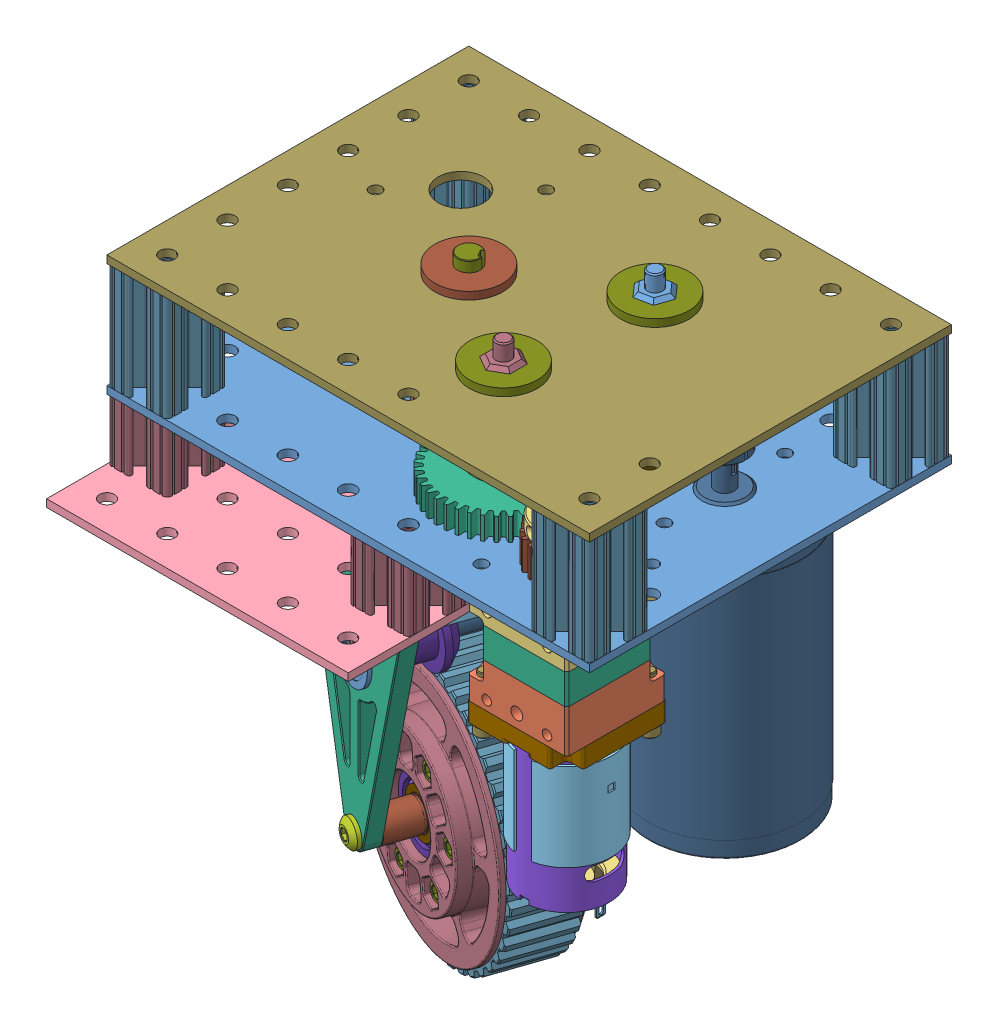
SolidWorks assembly Swerve V2.5 ASM 3_29_14, configuration Default. Lengths in mm.
Overall size (209.41 278.23 177.8).
183 component instances, 89 part files, 115 mates.
Components (placement in the parent):
- Middle Plate V2.5-1: Middle Plate V2.5 [Default] at (-68.3176 37.1134 -104.1218) x (1 0 0) z (0 0 -1) size (203.2 3.17 152.4)
- VEXpro_VersaPlanetary_with_AM9015-1: VEXpro_VersaPlanetary_with_AM9015 [Default] at (93.5566 -4.8866 16.5282) x (0 0 1) z (0 -1 0) size (42.75 42.7 160.22)
  - 217-2625-001 Rev1-1: 217-2625-001 Rev1 [Default] at origin size (42 42 18)
  - 217-2625-002 Rev1-1: 217-2625-002 Rev1 [Default] at (0 0 -16.7) size (42 42 17.13)
  - 217-2625-003 Rev1-1: 217-2625-003 Rev1 [Default] at (0 0 -30.9478) x (1 0 0) z (0 0 -1) size (17 17 64.12)
  - 217-2625-009 Rev1-1: 217-2625-009 Rev1 [Default] at (0 0 -3.48) x (0 -1 0) z (0 0 -1) size (18 18 13)
  - 217-2816-001 Rev1-1: 217-2816-001 Rev1 [Default] at (0 0 -16.85) x (1 0 0) z (0 0 -1) size (42 42 14.5)
  - 217-2625-007 Rev1_Sun_Driver01-1: 217-2625-007 Rev1_Sun_Driver01 [Default] at (0 0 -11.767) x (0.055822 0.998441 0) z (0 0 1) size (14.49 14.49 12.72)
  - 217-2625-100-1: 217-2625-100 [Default] at (0 0 -18.467) x (0 1 0) z (0 0 1) size (39.26 38.9 12.7)
    - 217-2625-008 Rev1-1: 217-2625-008 Rev1 [Default] at origin size (34.7 34.7 4.7)
    - 217-2625-010 Rev1-1: 217-2625-010 Rev1 [Default] at (0 10.193 3.65) x (0.999813 0.019336 0) z (0 0 1) size (4 4 12)
    - 217-2625-010 Rev1-2: 217-2625-010 Rev1 [Default] at (8.691 -5.3258 3.65) size (4 4 12)
    - 217-2625-010 Rev1-3: 217-2625-010 Rev1 [Default] at (-8.691 -5.3258 3.65) size (4 4 12)
    - 217-2625-005 Rev1_Planet_Revolving_Follower01-1: 217-2625-005 Rev1_Planet_Revolving_Follower01 [Default] at (8.691 -5.3258 6.35) x (0.932816 0.360354 0) z (0 0 1) size (16.91 16.92 8)
    - 217-2625-005 Rev1_Planet_Revolving_Follower01-2: 217-2625-005 Rev1_Planet_Revolving_Follower01 [Default] at (-8.691 -5.3258 6.35) x (-0.932788 -0.360426 0) z (0 0 1) size (16.91 16.92 8)
    - 217-2625-005 Rev1_Planet_Revolving_Follower01-3: 217-2625-005 Rev1_Planet_Revolving_Follower01 [Default] at (0 10.193 6.35) x (0.893583 0.448898 0) z (0 0 1) size (16.91 16.92 8)
  - 217-2625-014 Rev1-1: 217-2625-014 Rev1 [Default] at (0 0 1.2558) x (-1 0 0) z (0 -1 0) size (8 7.5 7.93)
  - SSA_SSA0832-0750ZC-1: SSA_SSA0832-0750ZC [Default] at (-17.4921 -17.5079 15.5) x (0.008716 -0.999962 0) z (-0.999962 -0.008716 0) size (6.73 23.11 6.73)
  - 217-2742-1: 217-2742 [Default] at (0 0 -30.4002) x (0 0 1) z (-1 0 0) size (7 28 28)
  - 217-2742-2: 217-2742 [Default] at (0 0 -38.7002) x (0 0 1) z (-0.997393 0.072165 0) size (7 28 28)
  - SSA_SSA0832-1250ZC-1: SSA_SSA0832-1250ZC [Default] at (17.5 -17.5 -34.561) x (1 0 0) z (0 1 0) size (6.73 35.81 6.73)
  - SSA_SSA0832-1250ZC-2: SSA_SSA0832-1250ZC [Default] at (-17.5 17.5 -34.561) x (1 0 0) z (0 1 0) size (6.73 35.81 6.73)
  - SSS1032-0125ZB_94105A824-1: SSS1032-0125ZB_94105A824 [Default] at (-6.908 0 1.995) x (0 -0.92485 0.380331) z (-1 0 0) size (4.83 4.84 3.3)
  - 217-2625-018 Rev1_98541A410-1: 217-2625-018 Rev1_98541A410 [Default] at (0 0 -22.7954) x (0 0 -1) z (0.980859 -0.194721 0) size (1 19.6 17.4)
  - 217-2625-017 Rev1_9714K61-1: 217-2625-017 Rev1_9714K61 [Default] at (0 0 -31.4002) x (-0.695225 0.718792 0) z (-0.718792 -0.695225 0) size (28.51 4.98 30.18)
  - PINL-M020-006-S-1: PINL-M020-006-S [Default] at (-18.5 13.6657 -9.5) x (0 0 -1) z (1 0 0) size (6 2 2)
  - PINL-M020-006-S-2: PINL-M020-006-S [Default] at (-18.5 13.6657 -22.2) x (0 0 -1) z (0.23951 -0.970894 0) size (6 2 2)
  - CCL-9015-am-0912-1: CCL-9015-am-0912 [Default] at (1.5904 1.123 40.182) x (0 0 1) z (1 0 0) size (82.02 37.83 37.47)
    - AM-0912 terminal-1: AM-0912 terminal [Default] at (29.27 -13.055 -1.5854) size (10.06 0.6 3.8)
    - AM-0912 output bushing-1: AM-0912 output bushing [Default] at (-28.166 1.123 -1.5904) size (4.5 10.97 10.97)
    - AM-0912 end cap-1: AM-0912 end cap [Default] at (24.952 1.123 -1.5904) size (6.48 34.65 34.46)
    - AM-0912 cap bushing-1: AM-0912 cap bushing [Default] at (31.302 1.123 -1.5904) size (3.04 8.08 8.08)
    - AM-0912 shield-1: AM-0912 shield [Default] at (-21.634 1.123 -1.5904) x (1 0 0) z (0 -1 0) size (36.88 37.47 37.83)
    - AM-0912 shaft-1: AM-0912 shaft [Default] at (-32.682 1.123 -1.5904) x (1 0 0) z (0 0.970706 0.240271) size (80.92 3.36 3.32)
    - AM-0912 terminal housing-1: AM-0912 terminal housing [Default] at (30.286 -13.101 -1.5904) x (-1 0 0) z (0 0 1) size (4.06 4.83 19.05)
    - AM-0912 terminal housing-2: AM-0912 terminal housing [Default] at (30.286 15.347 -1.5904) x (-1 0 0) z (0 0 -1) size (4.06 4.83 19.05)
    - AM-0912 terminal-2: AM-0912 terminal [Default] at (29.27 15.301 -1.5954) size (10.06 0.6 3.8)
    - AM-0912 housing-1: AM-0912 housing [Default] at (32.318 1.123 -1.5904) size (61.5 35.8 35.8)
  - SSA_SSA0832-0750ZC-2: SSA_SSA0832-0750ZC [Default] at (17.4921 17.5079 15.5) x (-0.008716 0.999962 0) z (0.999962 0.008716 0) size (6.73 23.11 6.73)
  - 217-2822-004 Rev4-1: 217-2822-004 Rev4 [Default] at (0 0 14.5) x (1 0.000449 0) z (0 0 1) size (42 42 9.8)
- 2_5 CIM Motor-1: 2_5 CIM Motor [Default] at (99.1446 26.9384 -44.4318) x (0 0 1) z (0 1 0) size (64.41 64.41 149.33)
- 50 tooth by 0.375 drive gear-2: 50 tooth by 0.375 drive gear [Default] at (-10.8801 58.1827 -17.093) x (1 0 0) z (0 -1 0) size (65.92 65.91 9.53) (hidden)
- 20 Tooth Steering Gear-1: 20 Tooth Steering Gear [Default] at (93.5566 43.4336 16.5282) x (0 0 -1) z (0 1 0) size (28.2 28.2 12.65)
- Top Plate V2.5-1: Top Plate V2.5 [Default] at (-68.343 84.7384 -104.1218) x (1 0 0) z (0 0 -1) size (203.2 3.17 152.4)
- 1020 - 0.875-1: 1020 - 0.875 [Default] at (-587.721 4.5981 961.277) x (0 0 -1) z (0 -1 0) size (25.4 50.8 22.23) (hidden)
- 1020 - 0.875-2: 1020 - 0.875 [Default] at (-587.721 4.5981 808.877) x (0 0 -1) z (0 -1 0) size (25.4 50.8 22.23) (hidden)
- 1020 - 0.875-3: 1020 - 0.875 [Default] at (-967.9477 -17.6269 -627.6227) x (1 0 0) z (0 -1 0) size (25.4 50.8 22.23) (hidden)
- 1020 -1.75-1: 1020 -1.75 [Default] at (-790.1477 78.3884 495.5791) x (1 0 0) z (0 1 0) size (25.4 50.8 44.45) (hidden)
- 1020 -1.75-2: 1020 -1.75 [Default] at (380.7388 -10.5116 942.2077) x (-0.837169 0 -0.546944) z (0 -1 0) size (25.4 50.8 44.45) (hidden)
- 1020 -1.75-3: 1020 -1.75 [Default] at (961.3238 -10.5116 -357.9119) x (-0.546944 0 0.837169) z (0 -1 0) size (25.4 50.8 44.45) (hidden)
- 1020 -1.75-4: 1020 -1.75 [Default] at (-541.0186 78.3884 -876.7519) x (0 0 1) z (0 1 0) size (25.4 50.8 44.45) (hidden)
- 14 Tooth 20 Pitch CIM Pinion-1: 14 Tooth 20 Pitch CIM Pinion [Default] at (99.1446 43.643 -44.4318) x (0.461445 0 -0.887169) z (0.887169 0 0.461445) size (20.28 9.53 20.28) (hidden)
- Hex Idler Shaft Steering-4: Hex Idler Shaft Steering [Default] at (56.752 60.1004 6.3682) x (0 0 1) z (0 -1 0) size (14.73 12.76 65.41)
- RushGears_2010_A2017-1: RushGears_2010_A2017 [2014.5A170.850.3750.380.380.95] at (99.1446 67.4029 -44.4318) x (1 0 0) z (0 -1 0) size (24.1 24.03 9.65)
- Revolution 2 Plaction+Steering Gear-1: Revolution 2 Plaction+Steering Gear [Default] at (-19.6614 -193.5925 -255.7146) x (0.992877 0 0.119145) z (-0.119145 0 0.992877) size (163.7 274.4 125.67)
  - Revolution 2 Plaction-1: Revolution 2 Plaction [Default] at (62.6202 125.584 106.4116) size (163.7 274.4 125.67)
    - cs_drive_hub_asm_1-1: cs_drive_hub_asm_1 [Default] at (28.1074 158.1318 104.3172) x (-0.796969 0 0.60402) z (-0.60402 0 -0.796969) size (89.7 127.05 89.7)
      - 5906K526_thrust_bushing_1-1: 5906K526_thrust_bushing_1 [Default] at (33.9501 -89.5224 3.5116) x (-0.279506 0 -0.960144) z (0 -1 0) size (63.5 63.5 3.17)
      - cs_vert_drive_shaft_1-1: cs_vert_drive_shaft_1 [Default] at (390.5574 -784.499 -2.4616) x (0 1 0) z (0.016748 0 0.99986) size (127.05 9.26 9.53)
      - 6843K12_miter_gear_1-1: 6843K12_miter_gear_1 [Default] at (36.0118 -122.8345 2.5948) x (-0.91373 0 0.406323) z (-0.406323 0 -0.91373) size (27.69 19.05 27.69)
      - revo2_pivot_hub-1: revo2_pivot_hub [Default] at (32.6196 -72.4841 4.7196) x (-0.740355 0 0.672216) z (-0.672216 0 -0.740355) size (63.5 46.42 63.5)
      - brf-06_1-1: brf-06_1 [Default] at (33.9501 -95.4787 3.5116) x (-0.582551 0 0.812794) z (0 -1 0) size (24.59 24.59 7.11)
      - brf-06_1-2: brf-06_1 [Default] at (33.9501 -53.0226 3.5116) x (-0.999614 0 -0.027772) z (0 1 0) size (24.59 24.59 7.11)
      - Imported_1-1: Imported_1 [Default] at (33.9501 -123.279 3.5116) x (0 -1 0) z (0.051397 0 0.998678) size (0.64 12.09 10.6)
      - Imported_1-2: Imported_1 [Default] at (33.9501 -49.0094 3.5116) x (0 1 0) z (0.82628 0 -0.563259) size (0.64 12.09 10.6)
      - large_thrust_bushing_1-1: large_thrust_bushing_1 [Default] at (33.9501 -102.2097 3.5116) x (1 0 0) z (0 -1 0) size (19.05 19.05 1.57)
      - bushing_backer_1-1: bushing_backer_1 [Default] at (33.9501 -99.0347 3.5116) x (1 0 0) z (0 -1 0) size (25.4 25.4 3.17)
    - cs_wheel_box_asm_plaction-1: cs_wheel_box_asm_plaction [Default] at (-5.7354 51.1469 144.7113) x (0.977946 0 0.20886) z (0 1 0) size (149.25 84.94 179.3)
      - revo2_wheel_box_cap-1: revo2_wheel_box_cap [Default] at origin size (63.5 63.5 9.53)
      - 6843K12_miter_gear_1-1: 6843K12_miter_gear_1 [Default] at (1.3308 15.2099 -25.4535) x (-0.668029 0 0.744136) z (0.744136 0 0.668029) size (27.69 19.05 27.69)
      - revo2_side_plate-1: revo2_side_plate [Default] at (-18.57 61.2601 -1.4632) x (1 0 0) z (0 -1 0) size (63.5 106.45 6.35)
      - revo2_side_plate-2: revo2_side_plate [Default] at (18.217 -14.9399 -1.4632) x (-1 0 0) z (0 1 0) size (63.5 106.45 6.35)
      - BHCS_91255A535-1: BHCS_91255A535 [Default] at (-0.1765 -14.9399 -90.5764) x (1 0 0) z (0 -1 0) size (11.23 11.23 13.63)
      - 91251A192_shcs-1: 91251A192_shcs [Default] at (-25.5765 51.7351 4.7625) x (1 0 0) z (0 -1 0) size (6.86 6.86 13.9)
      - 91251A192_shcs-2: 91251A192_shcs [Default] at (25.2235 51.7351 4.7625) x (1 0 0) z (0 -1 0) size (6.86 6.86 13.9)
      - 91251A192_shcs-3: 91251A192_shcs [Default] at (-8.6423 51.7351 4.7665) x (1 0 0) z (0 -1 0) size (6.86 6.86 13.9)
      - 91251A192_shcs-4: 91251A192_shcs [Default] at (8.2893 -5.4149 4.7665) x (1 0 0) z (0 1 0) size (6.86 6.86 13.9)
      - 91251A192_shcs-5: 91251A192_shcs [Default] at (-25.5765 -5.4149 4.7625) x (1 0 0) z (0 1 0) size (6.86 6.86 13.9)
      - 91251A192_shcs-6: 91251A192_shcs [Default] at (25.2235 -5.4149 4.7625) x (1 0 0) z (0 1 0) size (6.86 6.86 13.9)
      - brf-06_1-1: brf-06_1 [Default] at (-0.1765 59.2789 -23.7744) x (1 0 0) z (0 1 0) size (24.59 24.59 7.11)
      - brf-06_1-2: brf-06_1 [Default] at (-0.1765 -12.9587 -23.7744) x (0.755419 0 -0.655243) z (0 -1 0) size (24.59 24.59 7.11)
      - 16t_ws_globe_gear-1: 16t_ws_globe_gear [Default] at (2.3218 39.2687 -25.5275) x (0.818565 0 -0.574414) z (0.574414 0 0.818565) size (35.31 10.29 35.31)
      - revo2_cross_drive_shaft-1: revo2_cross_drive_shaft [Default] at (136.4364 723.0009 -354.9485) x (0 -1 0) z (-0.924435 0 -0.381339) size (83.39 9.26 9.53)
      - Imported_1-1: Imported_1 [Default] at (-0.1765 -16.9719 -23.7744) x (0 1 0) z (0 0 1) size (0.64 12.09 10.6)
      - Imported_1-2: Imported_1 [Default] at (-0.1765 63.4318 -23.7744) x (0 -1 0) z (0 0 1) size (0.64 12.09 10.6)
      - large_thrust_bushing_1-1: large_thrust_bushing_1 [Default] at (-0.1765 -5.4149 -23.7744) x (1 0 0) z (0 1 0) size (19.05 19.05 1.57)
      - 91251A192_shcs-7: 91251A192_shcs [Default] at (8.2893 51.7351 4.7645) x (1 0 0) z (0 -1 0) size (6.86 6.86 13.9)
      - 91251A192_shcs-8: 91251A192_shcs [Default] at (-8.6423 -5.4149 4.7645) x (1 0 0) z (0 1 0) size (6.86 6.86 13.9)
      - Imported_1-3: Imported_1 [Default] at (-0.1765 15.6544 -23.7744) x (0 -1 0) z (0 0 1) size (0.64 12.09 10.6)
      - Imported_1-4: Imported_1 [Default] at (-0.1765 48.5474 -23.7744) x (0 -1 0) z (0 0 1) size (0.64 12.09 10.6)
      - Imported_1-5: Imported_1 [Default] at (-0.1765 37.3714 -23.7744) x (0 1 0) z (0 0 1) size (0.64 12.09 10.6)
      - BHCS_91255A535-2: BHCS_91255A535 [Default] at (-0.1765 61.2601 -90.5764) x (0.396029 0 -0.918238) z (0 1 0) size (11.23 11.23 13.63)
      - revo2_wheel_shaft-1: revo2_wheel_shaft [Default] at (-0.1765 -8.5899 -90.5764) x (0.571408 0 0.820666) z (0 1 0) size (12.7 12.7 63.5)
      - AM_36t_sprocket-1: AM_36t_sprocket [Default] at (-0.1765 48.1029 -90.5764) x (0.524782 0 0.851237) z (0 -1 0) size (82.55 82.55 3.1)
      - 4Plaction-500bearing-1: 4Plaction-500bearing [Default] at (-0.1765 3.3481 -90.5764) x (0 1 0) z (-0.599972 0 0.800021) size (41.66 115.7 115.7)
        - 4MW_d011-1: 4MW_d011 [Default] at origin size (22.87 98.05 98.05)
        - 4MW_d011-2: 4MW_d011 [Default] at (41.656 0 0) x (-1 0 0) z (0 0 -1) size (22.87 98.05 98.05)
        - 4RoughTread1-1: 4RoughTread1 [Default] at (8.128 0 0) x (0 -0.992815 0.119662) z (1 0 0) size (104 104 25.4)
        - 10-32_nylock_nut1-1: 10-32_nylock_nut1 [Default] at (130.8703 19.4882 -76.5177) x (0 -0.340837 0.940122) z (-1 0 0) size (11.68 10.93 7.15)
        - 10-32_nylock_nut1-2: 10-32_nylock_nut1 [Default] at (130.8703 76.0104 -21.3816) x (0 -0.984588 0.174888) z (-1 0 0) size (11.68 10.93 7.15)
        - 10-32_nylock_nut1-3: 10-32_nylock_nut1 [Default] at (130.8703 56.5222 55.1361) x (0 -0.643751 -0.765235) z (-1 0 0) size (11.68 10.93 7.15)
        - 10-32_nylock_nut1-4: 10-32_nylock_nut1 [Default] at (130.8703 -19.4882 76.5177) x (0 0.340837 -0.940122) z (-1 0 0) size (11.68 10.93 7.15)
        - 10-32_nylock_nut1-5: 10-32_nylock_nut1 [Default] at (130.8703 -76.0104 21.3816) x (0 0.984588 -0.174888) z (-1 0 0) size (11.68 10.93 7.15)
        - 10-32_nylock_nut1-6: 10-32_nylock_nut1 [Default] at (130.8703 -56.5222 -55.1361) x (0 0.643751 0.765235) z (-1 0 0) size (11.68 10.93 7.15)
        - 10-32x1375_shcs1-1: 10-32x1375_shcs1 [Default] at (1.5748 0 23.8125) x (0 -0.961068 -0.276312) z (0 0.276312 -0.961068) size (7.82 39.7 7.82)
        - 10-32x1375_shcs1-2: 10-32x1375_shcs1 [Default] at (1.5748 -20.6222 11.9062) x (0 -0.241241 -0.970465) z (0 0.970465 -0.241241) size (7.82 39.7 7.82)
        - 10-32x1375_shcs1-3: 10-32x1375_shcs1 [Default] at (1.5748 -20.6222 -11.9062) x (0 0.719827 -0.694154) z (0 0.694154 0.719827) size (7.82 39.7 7.82)
        - 10-32x1375_shcs1-4: 10-32x1375_shcs1 [Default] at (1.5748 0 -23.8125) x (0 0.961068 0.276312) z (0 -0.276312 0.961068) size (7.82 39.7 7.82)
        - 10-32x1375_shcs1-5: 10-32x1375_shcs1 [Default] at (1.5748 20.6222 -11.9062) x (0 0.241241 0.970465) z (0 -0.970465 0.241241) size (7.82 39.7 7.82)
        - 10-32x1375_shcs1-6: 10-32x1375_shcs1 [Default] at (1.5748 20.6222 11.9062) x (0 -0.719827 0.694154) z (0 -0.694154 -0.719827) size (7.82 39.7 7.82)
      - ball_bearing_60355K150-1: ball_bearing_60355K150 [Default] at (-0.1765 38.5271 -90.5764) x (1 0 0) z (0 1 0) size (28.57 28.57 6.35)
        - NONE-1: NONE [Default] at origin size (28.57 28.57 6.35)
        - NONEA-1: NONEA [Default] at origin size (18.68 18.68 6.35)
        - NONEB-1: NONEB [Default] at origin size (3.43 3.43 3.43)
        - NONEC-1: NONEC [Default] at origin size (3.43 3.43 3.43)
        - NONED-1: NONED [Default] at origin size (3.43 3.43 3.43)
        - NONEE-1: NONEE [Default] at origin size (3.43 3.43 3.43)
        - NONEF-1: NONEF [Default] at origin size (3.43 3.43 3.43)
        - NONEG-1: NONEG [Default] at origin size (3.43 3.43 3.43)
        - NONEH-1: NONEH [Default] at origin size (3.43 3.43 3.43)
        - NONEI-1: NONEI [Default] at origin size (3.43 3.43 3.43)
        - NONEJ-1: NONEJ [Default] at origin size (3.43 3.43 3.43)
        - NONEK-1: NONEK [Default] at origin size (3.43 3.43 3.43)
      - ball_bearing_60355K150-2: ball_bearing_60355K150 [Default] at (-0.1765 9.8251 -90.5764) x (1 0 0) z (0 1 0) size (28.57 28.57 6.35)
        - NONE-1: NONE [Default] at origin size (28.57 28.57 6.35)
        - NONEA-1: NONEA [Default] at origin size (18.68 18.68 6.35)
        - NONEB-1: NONEB [Default] at origin size (3.43 3.43 3.43)
        - NONEC-1: NONEC [Default] at origin size (3.43 3.43 3.43)
        - NONED-1: NONED [Default] at origin size (3.43 3.43 3.43)
        - NONEE-1: NONEE [Default] at origin size (3.43 3.43 3.43)
        - NONEF-1: NONEF [Default] at origin size (3.43 3.43 3.43)
        - NONEG-1: NONEG [Default] at origin size (3.43 3.43 3.43)
        - NONEH-1: NONEH [Default] at origin size (3.43 3.43 3.43)
        - NONEI-1: NONEI [Default] at origin size (3.43 3.43 3.43)
        - NONEJ-1: NONEJ [Default] at origin size (3.43 3.43 3.43)
        - NONEK-1: NONEK [Default] at origin size (3.43 3.43 3.43)
      - bushing_backer_1-1: bushing_backer_1 [Default] at (-0.1765 -5.4149 -23.7744) x (1 0 0) z (0 -1 0) size (25.4 25.4 3.17)
      - 90128A218-1: 90128A218 [Default] at (-22.1736 35.8601 14.097) size (7.92 7.92 14.58)
      - 90128A218-2: 90128A218 [Default] at (-22.1736 10.4601 14.097) x (0.5 0.866025 0) z (0 0 1) size (7.92 7.92 14.58)
      - 90128A218-3: 90128A218 [Default] at (-0.1765 -2.2399 14.097) x (-0.5 0.866025 0) z (0 0 1) size (7.92 7.92 14.58)
      - 90128A218-4: 90128A218 [Default] at (21.8205 10.4601 14.097) x (-1 0 0) z (0 0 1) size (7.92 7.92 14.58)
      - 90128A218-5: 90128A218 [Default] at (21.8205 35.8601 14.097) x (-0.5 -0.866025 0) z (0 0 1) size (7.92 7.92 14.58)
      - 90128A218-6: 90128A218 [Default] at (-0.1765 48.5601 14.097) x (0.5 -0.866025 0) z (0 0 1) size (7.92 7.92 14.58)
    - bushing_hub_asm_1-1: bushing_hub_asm_1 [Default] at (11.3553 106.7094 120.0903) x (0.988095 0 -0.153847) z (-0.153847 0 -0.988095) size (63.5 38.1 63.5)
      - revo2_steering_hub_1-1: revo2_steering_hub_1 [Default] at origin size (63.5 38.1 63.5)
      - 1_1-1: 1_1 [Default] at (-0.595 0 0) size (44.45 38.1 44.45)
  - 40 Tooth Steering Gear+Mounting Holes-2: 40 Tooth Steering Gear+Mounting Holes [default] at (61.5494 237.4369 228.4366) x (0.982925 0 0.184009) z (0 1 0) size (53.25 53.25 11.09)
  - fhcs_91253A238-2: fhcs_91253A238 [Default] at (71.8811 238.9736 216.3838) x (1 0 0) z (0 1 0) size (10.32 10.32 6.54)
  - fhcs_91253A238-3: fhcs_91253A238 [Default] at (66.8216 238.9736 243.4106) x (1 0 0) z (0 1 0) size (10.32 10.32 6.54)
  - fhcs_91253A238-4: fhcs_91253A238 [Default] at (45.9455 238.9736 225.5155) x (1 0 0) z (0 1 0) size (10.32 10.32 6.54)
- .5 in Hex Flange Bearing-1: .5 in Hex Flange Bearing [Default] at (56.752 87.9134 6.3682) x (-0.866025 0 -0.5) z (-0.5 0 0.866025) size (31.12 7.94 31.12)
- .5 in Hex Flange Bearing-2: .5 in Hex Flange Bearing [Default] at (56.752 30.7634 6.3682) x (0.866025 0 -0.5) z (0.5 0 0.866025) size (31.12 7.94 31.12)
- .5 in Hex Flange Bearing-3: .5 in Hex Flange Bearing [Default] at (63.4068 87.9134 -50.7818) x (-0.321696 0 0.946843) z (0.946843 0 0.321696) size (31.12 7.94 31.12)
- .5 in Hex Flange Bearing-4: .5 in Hex Flange Bearing [Default] at (63.4322 33.9384 -50.7818) x (-0.321696 0 0.946843) z (-0.946843 0 -0.321696) size (31.12 7.94 31.12)
- 40 Tooth Drive Idler Gear-6: 40 Tooth Drive Idler Gear [Default] at (63.4322 62.5134 -50.7818) x (-0.194824 0 -0.980838) z (0 1 0) size (53.62 53.62 9.53)
- Bearing Spacer-2: Bearing Spacer [Default] at (63.4322 37.1134 -50.7818) size (44.45 3.17 44.45)
- Hex Idler Shaft Drive-5: Hex Idler Shaft Drive [Default] at (63.4322 61.6879 -50.7818) x (-0.321696 0 0.946843) z (0 -1 0) size (14.73 12.76 62.23)
- 50 tooth by 0.375 drive gear-3: 50 tooth by 0.375 drive gear [Default] at (14.2324 59.3384 -21.5718) x (0.996485 0 -0.083776) z (0 -1 0) size (65.92 65.91 9.53)
- .5 in Hex Collar-1: .5 in Hex Collar [Default] at (63.4322 54.5759 -50.7818) x (0.980838 0 -0.194824) z (0 -1 0) size (25.39 25.4 7.82)
- .5 in Hex Collar-2: .5 in Hex Collar [Default] at (63.4322 70.4509 -50.7818) x (0.980838 0 -0.194824) z (0 -1 0) size (25.39 25.4 7.82)
- .5 in Hex Collar-3: .5 in Hex Collar [Default] at (93.5566 52.9332 16.5282) x (0.5 0 0.866025) z (0 1 0) size (25.39 25.4 7.82)
- .5 in Hex Collar-5: .5 in Hex Collar [Default] at (56.752 54.5251 6.3682) x (0.982551 0 -0.185995) z (0 -1 0) size (25.39 25.4 7.82)
- Bottom Plate V2.5-2: Bottom Plate V2.5 [Default] at (-68.3176 8.5384 -104.1218) x (1 0 0) z (0 0 -1) size (127 3.17 177.8)
- .375 in Round Collar-1: .375 in Round Collar [Default] at (14.2324 54.5759 -21.5718) x (1 0 0) z (0 -1 0) size (22.21 22.23 6.35)
- .375 in Round Collar-2: .375 in Round Collar [Default] at (14.2324 70.4509 -21.5718) x (1 0 0) z (0 -1 0) size (22.21 22.23 6.35)
- 40 Tooth Gear-7: 40 Tooth Gear [Default] at (56.752 45.0255 6.3682) x (1 0 0) z (0 1 0) size (53.62 53.62 12.65)
- .0265 Hex D Spacer .5 Wide-1: .0265 Hex D Spacer .5 Wide [Default] at (93.5566 36.6074 16.5282) x (1 0 0) z (0 1 0) size (19.5 19.5 1.59)
- .5 in Hex Collar-7: .5 in Hex Collar [Default] at (63.4322 46.6384 -50.7818) x (1 0 0) z (0 1 0) size (25.39 25.4 7.82)
- .5 in Hex Collar-8: .5 in Hex Collar [Default] at (56.752 70.4509 6.3682) x (1 0 0) z (0 1 0) size (25.39 25.4 7.82)
- .0625 in Hex Delrin Spacer .5 Wide-2: .0625 in Hex Delrin Spacer .5 Wide [Default] at (63.4322 42.6697 -50.7818) x (0.321696 0 -0.946843) z (0 1 0) size (19.5 19.5 1.59)
- .25 in Hex Delrin Spacer .5 Wide-1: .25 in Hex Delrin Spacer .5 Wide [Default] at (63.4322 76.8009 -50.7818) x (0.321696 0 -0.946843) z (0 1 0) size (19.5 19.5 6.35)
- .25 in Hex Delrin Spacer .5 Wide-2: .25 in Hex Delrin Spacer .5 Wide [Default] at (56.752 76.8009 6.3682) x (0 0 -1) z (0 -1 0) size (19.5 19.5 6.35)
- CIM Collar-1: CIM Collar [Default] at (99.1446 54.5759 -44.4318) x (1 0 0) z (0 -1 0) size (17.99 18 6.35)
- .375x1.125 in Flanged Bearing-1: .375x1.125 in Flanged Bearing [Default] at (14.2324 87.9134 -21.5718) x (-0.837169 0 -0.546944) z (-0.546944 0 0.837169) size (31.12 7.94 31.12)
- .25 in Hex Delrin Spacer .375 Wide-1: .25 in Hex Delrin Spacer .375 Wide [Default] at (14.2324 76.8009 -21.5718) x (1 0 0) z (0 1 0) size (15.88 15.88 6.35)
- 1.0 in 8020 Stand-1: 1.0 in 8020 Stand [Default] at (-855.9566 8.5384 -680.2626) x (1 0 0) z (0 -1 0) size (25.4 25.4 25.4)
- 1.0 in 8020 Stand-2: 1.0 in 8020 Stand [Default] at (-855.9566 8.5384 -553.2626) x (1 0 0) z (0 -1 0) size (25.4 25.4 25.4)
- 1.0 in 8020 Stand-3: 1.0 in 8020 Stand [Default] at (-754.3566 8.5384 -553.2626) x (1 0 0) z (0 -1 0) size (25.4 25.4 25.4)
- 1.0 in 8020 Stand-4: 1.0 in 8020 Stand [Default] at (-754.3566 33.9384 497.419) x (1 0 0) z (0 1 0) size (25.4 25.4 25.4)
- 1.75 in 8020 Stand-1: 1.75 in 8020 Stand [Default] at (-855.9566 37.1134 -553.2626) x (1 0 0) z (0 -1 0) size (25.4 25.4 44.45)
- 1.75 in 8020 Stand-2: 1.75 in 8020 Stand [Default] at (-678.1566 37.1134 -553.2626) x (1 0 0) z (0 -1 0) size (25.4 25.4 44.45)
- 1.75 in 8020 Stand-3: 1.75 in 8020 Stand [Default] at (-678.1566 37.1134 -680.2626) x (1 0 0) z (0 -1 0) size (25.4 25.4 44.45)
- 1.75 in 8020 Stand-4: 1.75 in 8020 Stand [Default] at (-855.9566 37.1134 -680.2626) x (1 0 0) z (0 -1 0) size (25.4 25.4 44.45)
Mates (geometry in assembly coordinates):
- Coincident11: coincident anti-aligned: plane of Middle Plate V2.5-1 through (-68.3176 33.9384 -104.1218) normal (0 -1 0); plane of 2_5 CIM Motor-1 through (99.1446 33.9384 -44.4318) normal (0 1 0)
- Distance4: distance = 3.429 mm aligned: plane of 50 tooth by 0.375 drive gear-2 through (-4.1614 66.1202 13.0744) normal (0 1 0); plane of 2_5 CIM Motor-1 through (99.1446 69.5492 -44.4318) normal (0 1 0)
- Distance5: distance = 44.45 mm anti-aligned: plane of Top Plate V2.5-1 through (-68.343 81.5634 -104.1218) normal (0 -1 0); plane of Middle Plate V2.5-1 through (-68.3176 37.1134 -104.1218) normal (0 1 0)
- Concentric15: concentric aligned: cylinder of Top Plate V2.5-1 through (56.752 106.9634 6.3682) axis (0 -1 0) radius 14.2875; cylinder of Middle Plate V2.5-1 through (56.752 84.7384 6.3682) axis (0 -1 0) radius 14.2875
- Concentric18: concentric aligned: cylinder of Middle Plate V2.5-1 through (-55.6176 39.0184 -15.2218) axis (0 -1 0) radius 3.2512; cylinder of 1020 - 0.875-3 through (-55.6176 4.5981 -15.2218) axis (0 -1 0) radius 2.6035
- Concentric19: concentric aligned: cylinder of Middle Plate V2.5-1 through (-55.6176 39.0184 -40.6218) axis (0 -1 0) radius 3.2512; cylinder of 1020 - 0.875-3 through (-55.6176 4.5981 -40.6218) axis (0 -1 0) radius 2.6035
- Concentric22: concentric anti-aligned: cylinder of Middle Plate V2.5-1 through (122.1824 39.0184 -91.4218) axis (0 -1 0) radius 3.2512; cylinder of 1020 -1.75-1 through (122.1824 33.9384 -91.4218) axis (0 1 0) radius 2.6035
- Coincident19: coincident aligned: plane of Middle Plate V2.5-1 through (-68.3176 33.9384 -104.1218) normal (0 -1 0); plane of 1020 -1.75-1 through (134.8824 33.9384 -106.7634) normal (0 -1 0)
- Concentric25: concentric anti-aligned: cylinder of Middle Plate V2.5-1 through (45.9824 39.0184 35.5782) axis (0 -1 0) radius 3.2512; cylinder of 1020 -1.75-4 through (45.9824 33.9384 35.5782) axis (0 1 0) radius 2.6035
- Coincident20: coincident aligned: plane of Middle Plate V2.5-1 through (-68.3176 33.9384 -104.1218) normal (0 -1 0); plane of 1020 -1.75-4 through (61.324 33.9384 48.2782) normal (0 -1 0)
- Coincident21: coincident anti-aligned: plane of Middle Plate V2.5-1 through (-68.3176 33.9384 -104.1218) normal (0 -1 0); plane of 1020 -1.75-2 through (-64.2201 33.9384 -67.9946) normal (0 1 0)
- Coincident22: coincident anti-aligned: plane of Middle Plate V2.5-1 through (-68.3176 33.9384 -104.1218) normal (0 -1 0); plane of 1020 -1.75-3 through (-48.8785 33.9384 87.047) normal (0 1 0)
- Concentric49: concentric anti-aligned: cylinder of 2_5 CIM Motor-1 through (99.1446 37.9262 -44.4318) axis (0 1 0) radius 3.9751; cylinder of 14 Tooth 20 Pitch CIM Pinion-1 through (99.1446 53.168 -44.4318) axis (0 -1 0) radius 4
- Concentric59: concentric anti-aligned: cylinder of 2_5 CIM Motor-1 through (99.1446 37.9262 -44.4318) axis (0 1 0) radius 3.9751; cylinder of RushGears_2010_A2017-1 through (99.1446 12767.4029 -44.4318) axis (0 -1 0) radius 3.9624
- Parallel2: parallel aligned: plane of Middle Plate V2.5-1 through (-68.3176 33.9384 48.2782) normal (0 0 1); plane of Top Plate V2.5-1 through (-68.343 81.5634 48.2782) normal (0 0 1)
- Concentric61: concentric aligned: cylinder of Top Plate V2.5-1 through (56.752 106.9634 6.3682) axis (0 -1 0) radius 14.2875; cylinder of .5 in Hex Flange Bearing-1 through (56.752 87.9134 6.3682) axis (0 -1 0) radius 14.2748
- Coincident42: coincident anti-aligned: plane of Top Plate V2.5-1 through (-68.343 81.5634 -104.1218) normal (0 -1 0); plane of .5 in Hex Flange Bearing-1 through (43.2788 81.5634 -1.4106) normal (0 1 0)
- Concentric62: concentric anti-aligned: cylinder of Middle Plate V2.5-1 through (56.752 84.7384 6.3682) axis (0 -1 0) radius 14.2875; cylinder of .5 in Hex Flange Bearing-2 through (56.752 30.7634 6.3682) axis (0 1 0) radius 14.2748
- Parallel3: parallel anti-aligned: plane of Hex Idler Shaft Steering-4 through (59.9415 30.7624 11.8927) normal (0.5 0 0.866025); plane of .5 in Hex Flange Bearing-1 through (63.112 87.9134 10.0401) normal (-0.5 0 -0.866025)
- Parallel4: parallel anti-aligned: plane of Hex Idler Shaft Steering-4 through (59.9415 30.7624 11.8927) normal (0.5 0 0.866025); plane of .5 in Hex Flange Bearing-2 through (56.752 30.7634 13.7121) normal (-0.5 0 -0.866025)
- Concentric64: concentric anti-aligned: circle of Middle Plate V2.5-1; circle of .5 in Hex Flange Bearing-4
- Concentric65: concentric aligned: circle of Top Plate V2.5-1; circle of .5 in Hex Flange Bearing-3
- Coincident50: coincident anti-aligned: plane of Top Plate V2.5-1 through (-68.343 81.5634 -104.1218) normal (0 -1 0); plane of .5 in Hex Flange Bearing-3 through (58.402 81.5634 -36.0513) normal (0 1 0)
- Concentric68: concentric aligned: cylinder of Hex Idler Shaft Steering-4 through (56.752 96.1684 6.3682) axis (0 1 0) radius 3.1623; circle of .5 in Hex Flange Bearing-1
- Concentric74: concentric anti-aligned: cylinder of Middle Plate V2.5-1 through (99.1446 84.7384 -44.4318) axis (0 -1 0) radius 9.525; cylinder of 2_5 CIM Motor-1 through (99.1446 33.9384 -44.4318) axis (0 1 0) radius 9.525
- Coincident63: coincident anti-aligned: plane of Middle Plate V2.5-1 through (-68.3176 37.1134 -104.1218) normal (0 1 0); plane of .5 in Hex Flange Bearing-2 through (70.2252 37.1134 -1.4106) normal (0 -1 0)
- Coincident64: coincident anti-aligned: plane of Middle Plate V2.5-1 through (-68.3176 37.1134 -104.1218) normal (0 1 0); plane of Bearing Spacer-2 through (63.4322 37.1134 -50.7818) normal (0 -1 0)
- Concentric78: concentric aligned: circle of Middle Plate V2.5-1; circle of Bearing Spacer-2
- Coincident65: coincident anti-aligned: plane of .5 in Hex Flange Bearing-4 through (58.4274 40.2884 -36.0513) normal (0 -1 0); plane of Bearing Spacer-2 through (63.4322 40.2884 -50.7818) normal (0 1 0)
- Coincident66: coincident aligned: plane of Hex Idler Shaft Steering-4 through (56.752 30.7634 13.7342) normal (0 -1 0); plane of .5 in Hex Flange Bearing-2 through (69.1143 30.7634 -0.7692) normal (0 -1 0)
- Concentric79: concentric anti-aligned: circle of .5 in Hex Flange Bearing-4; cylinder of Hex Idler Shaft Drive-5 through (63.4322 96.1684 -50.7818) axis (0 1 0) radius 3.1623
- Parallel12: parallel anti-aligned: plane of .5 in Hex Flange Bearing-3 through (58.5661 87.9134 -56.3046) normal (0.194824 0 0.980838); plane of Hex Idler Shaft Drive-5 through (62.1894 33.9374 -57.0387) normal (-0.194824 0 -0.980838)
- Parallel13: parallel aligned: plane of .5 in Hex Flange Bearing-4 through (61.0697 33.9384 -43.8283) normal (-0.194824 0 -0.980838); plane of Hex Idler Shaft Drive-5 through (62.1894 33.9374 -57.0387) normal (-0.194824 0 -0.980838)
- Coincident69: coincident aligned: plane of .5 in Hex Flange Bearing-4 through (58.84 33.9384 -37.2658) normal (0 -1 0); plane of Hex Idler Shaft Drive-5 through (61.0626 33.9384 -43.8074) normal (0 -1 0)
- Concentric80: concentric anti-aligned: cylinder of Revolution 2 Plaction+Steering Gear-1/Revolution 2 Plaction-1/cs_drive_hub_asm_1-1/cs_vert_drive_shaft_1-1 through (14.2324 66.933 -21.5718) axis (0 1 0) radius 4.7625; cylinder of 50 tooth by 0.375 drive gear-3 through (14.2324 67.2759 -21.5718) axis (0 -1 0) radius 4.7625
- Concentric81: concentric anti-aligned: cylinder of Hex Idler Shaft Drive-5 through (63.4322 96.1684 -50.7818) axis (0 1 0) radius 3.1623; circle of .5 in Hex Collar-1
- Concentric82: concentric anti-aligned: cylinder of Hex Idler Shaft Drive-5 through (63.4322 96.1684 -50.7818) axis (0 1 0) radius 3.1623; circle of .5 in Hex Collar-2
- Parallel14: parallel aligned: plane of Hex Idler Shaft Drive-5 through (62.1894 33.9374 -57.0387) normal (-0.194824 0 -0.980838); plane of .5 in Hex Collar-2 through (68.3619 73.6259 -45.1575) normal (-0.194824 0 -0.980838)
- Parallel15: parallel aligned: plane of Hex Idler Shaft Drive-5 through (62.1894 33.9374 -57.0387) normal (-0.194824 0 -0.980838); plane of .5 in Hex Collar-1 through (68.3619 57.7509 -45.1575) normal (-0.194824 0 -0.980838)
- Parallel16: parallel anti-aligned: plane of 40 Tooth Drive Idler Gear-6 through (58.5701 68.838 -56.329) normal (0.194824 0 0.980838); plane of Hex Idler Shaft Drive-5 through (62.1894 33.9374 -57.0387) normal (-0.194824 0 -0.980838)
- Concentric83: concentric anti-aligned: circle of 20 Tooth Steering Gear-1; circle of .5 in Hex Collar-3
- Coincident77: coincident anti-aligned: plane of 20 Tooth Steering Gear-1 through (93.5566 49.7582 16.5282) normal (0 1 0); plane of .5 in Hex Collar-3 through (93.5566 49.7582 16.5282) normal (0 -1 0)
- Concentric85: concentric anti-aligned: cylinder of Hex Idler Shaft Steering-4 through (56.752 96.1684 6.3682) axis (0 1 0) radius 3.1623; circle of .5 in Hex Collar-5
- Coincident84: coincident aligned: plane of Middle Plate V2.5-1 through (-68.3176 33.9384 -104.1218) normal (-1 0 0); plane of Bottom Plate V2.5-2 through (-68.3176 5.3634 -104.1218) normal (-1 0 0)
- Distance6: distance = 25.4 mm anti-aligned: plane of Bottom Plate V2.5-2 through (-68.3176 8.5384 -104.1218) normal (0 1 0); plane of Middle Plate V2.5-1 through (-68.3176 33.9384 -104.1218) normal (0 -1 0)
- Concentric88: concentric aligned: cylinder of Middle Plate V2.5-1 through (14.2324 84.7384 -21.5718) axis (0 -1 0) radius 25.4762; cylinder of Revolution 2 Plaction+Steering Gear-1/Revolution 2 Plaction-1/bushing_hub_asm_1-1/revo2_steering_hub_1-1 through (14.2324 38.7009 -21.5718) axis (0 -1 0) radius 25.4
- Coincident88: coincident anti-aligned: plane of Revolution 2 Plaction+Steering Gear-1/Revolution 2 Plaction-1/bushing_hub_asm_1-1/revo2_steering_hub_1-1 through (14.2324 5.3634 -21.5718) normal (0 1 0); plane of Bottom Plate V2.5-2 through (-68.3176 5.3634 -104.1218) normal (0 -1 0)
- Concentric89: concentric aligned: cylinder of Revolution 2 Plaction+Steering Gear-1/Revolution 2 Plaction-1/bushing_hub_asm_1-1/revo2_steering_hub_1-1 through (14.2324 38.7009 -21.5718) axis (0 -1 0) radius 25.4; cylinder of Bottom Plate V2.5-2 through (14.2324 8.5384 -21.5718) axis (0 -1 0) radius 25.4
- Concentric90: concentric anti-aligned: cylinder of Revolution 2 Plaction+Steering Gear-1/Revolution 2 Plaction-1/cs_drive_hub_asm_1-1/cs_vert_drive_shaft_1-1 through (14.2324 66.933 -21.5718) axis (0 1 0) radius 4.7625; circle of .375 in Round Collar-2
- Concentric91: concentric anti-aligned: cylinder of Revolution 2 Plaction+Steering Gear-1/Revolution 2 Plaction-1/cs_drive_hub_asm_1-1/cs_vert_drive_shaft_1-1 through (14.2324 66.933 -21.5718) axis (0 1 0) radius 4.7625; circle of .375 in Round Collar-1
- Coincident89: coincident anti-aligned: plane of 50 tooth by 0.375 drive gear-3 through (23.4548 67.2759 7.9267) normal (0 1 0); plane of .375 in Round Collar-2 through (14.2324 67.2759 -21.5718) normal (0 -1 0)
- Coincident90: coincident anti-aligned: plane of 50 tooth by 0.375 drive gear-3 through (23.4548 57.7509 7.9267) normal (0 -1 0); plane of .375 in Round Collar-1 through (14.2324 57.7509 -21.5718) normal (0 1 0)
- Concentric92: concentric aligned: circle of Middle Plate V2.5-1; circle of 40 Tooth Gear-7
- Parallel19: parallel aligned: plane of Hex Idler Shaft Steering-4 through (59.9415 30.7624 11.8927) normal (0.5 0 0.866025); plane of 40 Tooth Gear-7 through (50.3639 51.3501 2.68) normal (0.5 0 0.866025)
- Coincident92: coincident anti-aligned: plane of .5 in Hex Collar-5 through (56.752 51.3501 6.3682) normal (0 -1 0); plane of 40 Tooth Gear-7 through (56.752 51.3501 6.3682) normal (0 1 0)
- Coincident95: coincident anti-aligned: plane of .5 in Hex Flange Bearing-2 through (62.2512 38.7009 3.1932) normal (0 1 0); plane of 40 Tooth Gear-7 through (56.752 38.7009 6.3682) normal (0 -1 0)
- Coincident102: coincident aligned: plane of RushGears_2010_A2017-1 through (99.1446 57.7509 -44.4318) normal (0 -1 0); plane of 40 Tooth Drive Idler Gear-6 through (37.2732 57.7509 -45.5859) normal (0 -1 0)
- Concentric97: concentric anti-aligned: circle of .5 in Hex Flange Bearing-4; circle of .5 in Hex Collar-7
- Concentric98: concentric anti-aligned: circle of .5 in Hex Flange Bearing-4; circle of .0625 in Hex Delrin Spacer .5 Wide-2
- Parallel21: parallel anti-aligned: plane of Hex Idler Shaft Drive-5 through (62.1894 33.9374 -57.0387) normal (-0.194824 0 -0.980838); plane of .0625 in Hex Delrin Spacer .5 Wide-2 through (65.8381 43.4634 -57.8633) normal (0.194824 0 0.980838)
- Coincident104: coincident anti-aligned: plane of .5 in Hex Flange Bearing-4 through (61.3894 41.8759 -44.7694) normal (0 1 0); plane of .0625 in Hex Delrin Spacer .5 Wide-2 through (63.4322 41.8759 -50.7818) normal (0 -1 0)
- Coincident105: coincident anti-aligned: plane of .5 in Hex Collar-7 through (63.4322 43.4634 -50.7818) normal (0 -1 0); plane of .0625 in Hex Delrin Spacer .5 Wide-2 through (63.4322 43.4634 -50.7818) normal (0 1 0)
- Coincident110: coincident anti-aligned: plane of 40 Tooth Drive Idler Gear-6 through (63.4322 67.2759 -50.7818) normal (0 1 0); plane of .5 in Hex Collar-2 through (63.4322 67.2759 -50.7818) normal (0 -1 0)
- Concentric100: concentric anti-aligned: circle of Middle Plate V2.5-1; circle of 40 Tooth Drive Idler Gear-6
- Coincident111: coincident anti-aligned: plane of 40 Tooth Drive Idler Gear-6 through (37.2732 57.7509 -45.5859) normal (0 -1 0); plane of .5 in Hex Collar-1 through (63.4322 57.7509 -50.7818) normal (0 1 0)
- Concentric101: concentric anti-aligned: circle of .5 in Hex Flange Bearing-4; circle of .25 in Hex Delrin Spacer .5 Wide-1
- Parallel23: parallel anti-aligned: plane of Hex Idler Shaft Drive-5 through (62.1894 33.9374 -57.0387) normal (-0.194824 0 -0.980838); plane of .25 in Hex Delrin Spacer .5 Wide-1 through (65.8381 79.9759 -57.8633) normal (0.194824 0 0.980838)
- Coincident113: coincident anti-aligned: plane of .5 in Hex Flange Bearing-3 through (61.364 79.9759 -44.7694) normal (0 -1 0); plane of .25 in Hex Delrin Spacer .5 Wide-1 through (63.4322 79.9759 -50.7818) normal (0 1 0)
- Coincident114: coincident anti-aligned: plane of .5 in Hex Collar-2 through (63.4322 73.6259 -50.7818) normal (0 1 0); plane of .25 in Hex Delrin Spacer .5 Wide-1 through (63.4322 73.6259 -50.7818) normal (0 -1 0)
- Concentric102: concentric anti-aligned: circle of Middle Plate V2.5-1; circle of .5 in Hex Collar-8
- Concentric103: concentric anti-aligned: circle of Middle Plate V2.5-1; circle of .25 in Hex Delrin Spacer .5 Wide-2
- Parallel24: parallel anti-aligned: plane of Hex Idler Shaft Steering-4 through (53.5624 30.7624 11.8927) normal (-0.5 0 0.866025); plane of .25 in Hex Delrin Spacer .5 Wide-2 through (56.752 73.6259 13.8472) normal (0.5 0 -0.866025)
- Coincident116: coincident anti-aligned: plane of .5 in Hex Collar-8 through (56.752 73.6259 6.3682) normal (0 1 0); plane of .25 in Hex Delrin Spacer .5 Wide-2 through (56.752 73.6259 6.3682) normal (0 -1 0)
- Coincident117: coincident anti-aligned: plane of .5 in Hex Flange Bearing-1 through (51.2527 79.9759 3.1932) normal (0 -1 0); plane of .25 in Hex Delrin Spacer .5 Wide-2 through (56.752 79.9759 6.3682) normal (0 1 0)
- Concentric105: concentric anti-aligned: circle of 2_5 CIM Motor-1; circle of CIM Collar-1
- Coincident118: coincident aligned: plane of RushGears_2010_A2017-1 through (99.1446 57.7509 -44.4318) normal (0 -1 0); circle of CIM Collar-1
- Coincident122: coincident anti-aligned: plane of Top Plate V2.5-1 through (-68.343 81.5634 -104.1218) normal (0 -1 0); plane of .375x1.125 in Flanged Bearing-1 through (1.2081 81.5634 -30.0809) normal (0 1 0)
- Concentric108: concentric aligned: cylinder of Revolution 2 Plaction+Steering Gear-1/Revolution 2 Plaction-1/cs_drive_hub_asm_1-1/cs_vert_drive_shaft_1-1 through (14.2324 66.933 -21.5718) axis (0 1 0) radius 4.7625; circle of .375x1.125 in Flanged Bearing-1
- Concentric109: concentric anti-aligned: cylinder of Revolution 2 Plaction+Steering Gear-1/Revolution 2 Plaction-1/cs_drive_hub_asm_1-1/cs_vert_drive_shaft_1-1 through (14.2324 66.933 -21.5718) axis (0 1 0) radius 4.7625; circle of .25 in Hex Delrin Spacer .375 Wide-1
- Coincident123: coincident anti-aligned: plane of .375x1.125 in Flanged Bearing-1 through (10.2454 79.9759 -24.1766) normal (0 -1 0); plane of .25 in Hex Delrin Spacer .375 Wide-1 through (14.2324 79.9759 -21.5718) normal (0 1 0)
- Coincident124: coincident anti-aligned: plane of .375 in Round Collar-2 through (14.2324 73.6259 -21.5718) normal (0 1 0); plane of .25 in Hex Delrin Spacer .375 Wide-1 through (14.2324 73.6259 -21.5718) normal (0 -1 0)
- Coincident125: coincident anti-aligned: plane of Bottom Plate V2.5-2 through (-68.3176 8.5384 -104.1218) normal (0 1 0); plane of 1.0 in 8020 Stand-2 through (-42.9176 8.5384 25.5198) normal (0 -1 0)
- Concentric110: concentric aligned: cylinder of 1.0 in 8020 Stand-2 through (-55.6176 33.9384 35.5782) axis (0 -1 0) radius 2.6035; cylinder of Bottom Plate V2.5-2 through (-55.6176 8.5384 35.5782) axis (0 -1 0) radius 3.175
- Coincident126: coincident aligned: plane of Bottom Plate V2.5-2 through (-68.3176 5.3634 -104.1218) normal (-1 0 0); plane of 1.0 in 8020 Stand-2 through (-68.3176 33.9384 45.1286) normal (-1 0 0)
- Coincident127: coincident anti-aligned: plane of Bottom Plate V2.5-2 through (-68.3176 8.5384 -104.1218) normal (0 1 0); plane of 1.0 in 8020 Stand-1 through (-42.9176 8.5384 -101.4802) normal (0 -1 0)
- Concentric111: concentric aligned: cylinder of Bottom Plate V2.5-2 through (-55.6176 8.5384 -91.4218) axis (0 -1 0) radius 3.175; cylinder of 1.0 in 8020 Stand-1 through (-55.6176 33.9384 -91.4218) axis (0 -1 0) radius 2.6035
- Coincident128: coincident aligned: plane of Bottom Plate V2.5-2 through (-68.3176 5.3634 -104.1218) normal (-1 0 0); plane of 1.0 in 8020 Stand-1 through (-68.3176 33.9384 -81.8714) normal (-1 0 0)
- Coincident129: coincident anti-aligned: plane of Bottom Plate V2.5-2 through (-68.3176 8.5384 -104.1218) normal (0 1 0); plane of 1.0 in 8020 Stand-3 through (58.6824 8.5384 25.5198) normal (0 -1 0)
- Concentric112: concentric aligned: cylinder of Bottom Plate V2.5-2 through (45.9824 8.5384 35.5782) axis (0 -1 0) radius 3.175; cylinder of 1.0 in 8020 Stand-3 through (45.9824 33.9384 35.5782) axis (0 -1 0) radius 2.6035
- Coincident130: coincident aligned: plane of Bottom Plate V2.5-2 through (58.6824 5.3634 -104.1218) normal (1 0 0); plane of 1.0 in 8020 Stand-3 through (58.6824 33.9384 42.1822) normal (1 0 0)
- Coincident131: coincident anti-aligned: plane of Bottom Plate V2.5-2 through (-68.3176 8.5384 -104.1218) normal (0 1 0); plane of 1.0 in 8020 Stand-4 through (58.6824 8.5384 -81.3634) normal (0 -1 0)
- Concentric113: concentric anti-aligned: cylinder of Bottom Plate V2.5-2 through (45.9824 8.5384 -91.4218) axis (0 -1 0) radius 3.175; cylinder of 1.0 in 8020 Stand-4 through (45.9824 8.5384 -91.4218) axis (0 1 0) radius 2.6035
- Coincident132: coincident aligned: plane of Bottom Plate V2.5-2 through (-68.3176 5.3634 -104.1218) normal (0 0 -1); plane of 1.0 in 8020 Stand-4 through (39.3784 8.5384 -104.1218) normal (0 0 -1)
- Coincident133: coincident anti-aligned: plane of Middle Plate V2.5-1 through (-68.3176 37.1134 -104.1218) normal (0 1 0); plane of 1.75 in 8020 Stand-1 through (-42.9176 37.1134 25.5198) normal (0 -1 0)
- Coincident134: coincident anti-aligned: plane of Middle Plate V2.5-1 through (-68.3176 37.1134 -104.1218) normal (0 1 0); plane of 1.75 in 8020 Stand-4 through (-42.9176 37.1134 -101.4802) normal (0 -1 0)
- Coincident135: coincident anti-aligned: plane of Middle Plate V2.5-1 through (-68.3176 37.1134 -104.1218) normal (0 1 0); plane of 1.75 in 8020 Stand-3 through (134.8824 37.1134 -101.4802) normal (0 -1 0)
- Coincident136: coincident anti-aligned: plane of Middle Plate V2.5-1 through (-68.3176 37.1134 -104.1218) normal (0 1 0); plane of 1.75 in 8020 Stand-2 through (134.8824 37.1134 25.5198) normal (0 -1 0)
- Coincident137: coincident aligned: plane of Middle Plate V2.5-1 through (-68.3176 33.9384 48.2782) normal (0 0 1); plane of 1.75 in 8020 Stand-1 through (-46.0672 81.5634 48.2782) normal (0 0 1)
- Concentric114: concentric aligned: cylinder of Middle Plate V2.5-1 through (-55.6176 39.0184 35.5782) axis (0 -1 0) radius 3.2512; cylinder of 1.75 in 8020 Stand-1 through (-55.6176 81.5634 35.5782) axis (0 -1 0) radius 2.6035
- Coincident138: coincident aligned: plane of Middle Plate V2.5-1 through (-68.3176 33.9384 -104.1218) normal (0 0 -1); plane of 1.75 in 8020 Stand-4 through (-65.168 81.5634 -104.1218) normal (0 0 -1)
- Concentric115: concentric aligned: cylinder of Middle Plate V2.5-1 through (-55.6176 39.0184 -91.4218) axis (0 -1 0) radius 3.2512; cylinder of 1.75 in 8020 Stand-4 through (-55.6176 81.5634 -91.4218) axis (0 -1 0) radius 2.6035
- Coincident139: coincident aligned: plane of Middle Plate V2.5-1 through (-68.3176 33.9384 -104.1218) normal (0 0 -1); plane of 1.75 in 8020 Stand-3 through (128.7864 81.5634 -104.1218) normal (0 0 -1)
- Concentric116: concentric aligned: cylinder of Middle Plate V2.5-1 through (122.1824 39.0184 -91.4218) axis (0 -1 0) radius 3.2512; cylinder of 1.75 in 8020 Stand-3 through (122.1824 81.5634 -91.4218) axis (0 -1 0) radius 2.6035
- Concentric117: concentric aligned: cylinder of Middle Plate V2.5-1 through (122.1824 39.0184 35.5782) axis (0 -1 0) radius 3.2512; cylinder of 1.75 in 8020 Stand-2 through (122.1824 81.5634 35.5782) axis (0 -1 0) radius 2.6035
- Coincident140: coincident aligned: plane of Middle Plate V2.5-1 through (-68.3176 33.9384 48.2782) normal (0 0 1); plane of 1.75 in 8020 Stand-2 through (131.7328 81.5634 48.2782) normal (0 0 1)
- Parallel25: parallel aligned: plane of Middle Plate V2.5-1 through (134.8824 33.9384 -104.1218) normal (1 0 0); plane of VEXpro_VersaPlanetary_with_AM9015-1/217-2625-002 Rev1-1 through (114.5566 33.9384 37.5282) normal (1 0 0)
- Concentric118: concentric anti-aligned: cylinder of Middle Plate V2.5-1 through (93.5566 84.7384 16.5282) axis (0 -1 0) radius 9.5504; cylinder of VEXpro_VersaPlanetary_with_AM9015-1/217-2625-003 Rev1-1 through (93.5566 33.8136 16.5282) axis (0 1 0) radius 8.5
- Concentric119: concentric aligned: circle of Middle Plate V2.5-1; cylinder of .0265 Hex D Spacer .5 Wide-1 through (93.5566 35.8136 16.5282) axis (0 1 0) radius 9.75
- Parallel26: parallel aligned: plane of VEXpro_VersaPlanetary_with_AM9015-1/217-2625-003 Rev1-1 through (89.8904 75.8136 22.8782) normal (0 0 1); plane of .0265 Hex D Spacer .5 Wide-1 through (89.8171 35.8136 10.0512) normal (0 0 1)
- Coincident146: coincident anti-aligned: plane of Middle Plate V2.5-1 through (-68.3176 33.9384 -104.1218) normal (0 -1 0); plane of VEXpro_VersaPlanetary_with_AM9015-1/217-2625-002 Rev1-1 through (72.5566 33.9384 -4.4718) normal (0 1 0)
- Coincident147: coincident anti-aligned: plane of VEXpro_VersaPlanetary_with_AM9015-1/217-2625-003 Rev1-1 through (93.5566 35.8136 16.5282) normal (0 1 0); plane of .0265 Hex D Spacer .5 Wide-1 through (93.5566 35.8136 16.5282) normal (0 -1 0)
- Parallel28: parallel aligned: plane of VEXpro_VersaPlanetary_with_AM9015-1/217-2625-003 Rev1-1 through (89.8904 75.8136 22.8782) normal (0 0 1); plane of .5 in Hex Collar-3 through (97.2961 49.7582 10.0512) normal (0 0 1)
- Parallel29: parallel aligned: plane of 20 Tooth Steering Gear-1 through (86.1802 49.7582 16.5282) normal (0.866025 0 0.5); plane of .5 in Hex Collar-3 through (89.8171 49.7582 10.0512) normal (0.866025 0 0.5)
- Coincident154: coincident anti-aligned: plane of 20 Tooth Steering Gear-1 through (90.1187 37.4011 5.9475) normal (0 -1 0); plane of .0265 Hex D Spacer .5 Wide-1 through (93.5566 37.4011 16.5282) normal (0 1 0)
- Concentric122: concentric aligned: circle of .5 in Hex Collar-3; circle of .0265 Hex D Spacer .5 Wide-1
